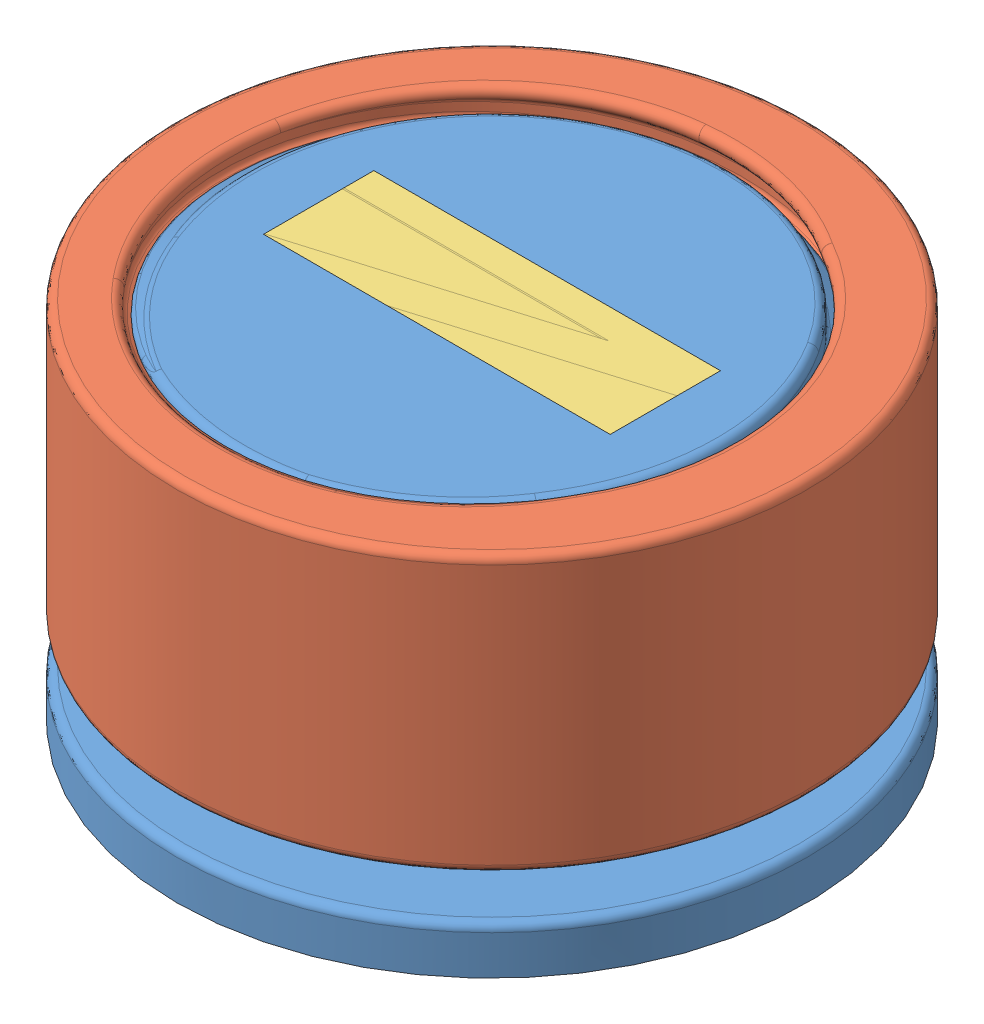
SolidWorks assembly bulkhead assembly, configuration Default. Lengths in mm.
Overall size (65.64 30.55 65.64).
4 component instances, 3 part files, 8 mates.
Components (placement in the parent):
- bulkhead body-1: bulkhead body [Default] at (8.061 -27.7408 8.1049) size (50.8 30.39 50.8)
- bulkhead nut-1: bulkhead nut [Default] at (8.061 -24.3027 8.1049) x (0.35854 0 0.933514) z (-0.933514 0 0.35854) size (50.8 24.37 50.8)
- 8694K141_Light Duty Blended EPDM Foam Strip-1: 8694K141_Light Duty Blended EPDM Foam Strip [8694K141] at (8.061 -17.5808 9.6924) x (1 0 0) z (0 -1 0) size (31.75 9.65 27.94)
- 8694K141_Light Duty Blended EPDM Foam Strip-2: 8694K141_Light Duty Blended EPDM Foam Strip [8694K141] at (8.061 -17.5808 6.6444) x (1 0 0) z (0 -1 0) size (31.75 9.65 27.94)
Mates (geometry in assembly coordinates):
- Concentric1: concentric anti-aligned: cylinder of bulkhead nut-1 through (8.061 -2.0777 8.1049) axis (0 -1 0) radius 25.4; cylinder of bulkhead body-1 through (8.061 -31.5508 8.1049) axis (0 1 0) radius 25.4
- Screw1: screw = 1: cylinder of bulkhead body-1 through (8.061 -31.5508 8.1049) axis (0 1 0) radius 25.4; cylinder of bulkhead nut-1 through (8.061 -2.0777 8.1049) axis (0 -1 0) radius 25.4
- Coincident1: coincident anti-aligned: plane of bulkhead body-1 through (-7.814 -2.3408 14.4549) normal (0 0 -1); plane of 8694K141_Light Duty Blended EPDM Foam Strip-1 through (-7.814 -31.5508 14.4549) normal (0 0 1)
- Coincident2: coincident anti-aligned: plane of bulkhead body-1 through (23.936 -2.3408 1.7549) normal (-1 0 0); plane of 8694K141_Light Duty Blended EPDM Foam Strip-1 through (23.936 -31.5508 14.4549) normal (1 0 0)
- Coincident3: coincident aligned: plane of bulkhead body-1 through (8.061 -31.5508 8.1049) normal (0 -1 0); plane of 8694K141_Light Duty Blended EPDM Foam Strip-1 through (8.061 -31.5508 9.6924) normal (0 -1 0)
- Coincident7: coincident aligned: plane of bulkhead body-1 through (8.061 -31.5508 8.1049) normal (0 -1 0); plane of 8694K141_Light Duty Blended EPDM Foam Strip-2 through (8.061 -31.5508 6.6444) normal (0 -1 0)
- Coincident8: coincident anti-aligned: plane of bulkhead body-1 through (23.936 -2.3408 1.7549) normal (-1 0 0); plane of 8694K141_Light Duty Blended EPDM Foam Strip-2 through (23.936 -31.5508 11.4069) normal (1 0 0)
- Coincident9: coincident anti-aligned: plane of bulkhead body-1 through (-7.814 -2.3408 1.7549) normal (0 0 1); plane of 8694K141_Light Duty Blended EPDM Foam Strip-2 through (8.061 -17.5808 1.7549) normal (0 0 -1)
